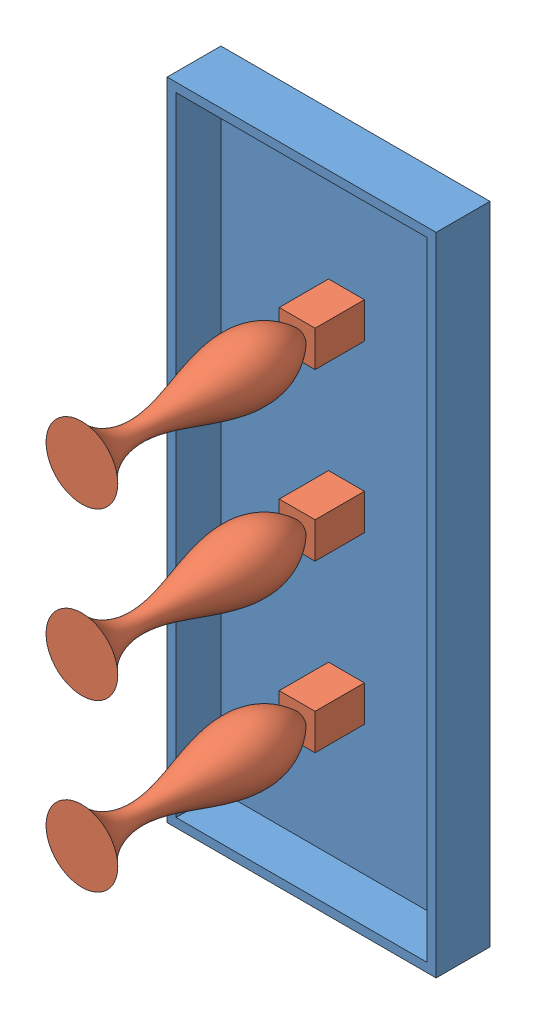
SolidWorks assembly Assem1, configuration Default. Lengths in mm.
Overall size (762 1828.8 774.7).
4 component instances, 2 part files, 9 mates.
Components (placement in the parent):
- Table_Top-1: Table_Top [Default] at (1737.8097 1152.1022 1538.3527) size (762 1828.8 152.4)
- Table_Leg-1: Table_Leg [Default] at (239.1087 1458.4963 2160.6527) x (1 0 0) z (0 1 0) size (237.21 762 237.21)
- Table_Leg-2: Table_Leg [Default] at (239.1087 988.5963 2160.6527) x (1 0 0) z (0 1 0) size (237.21 762 237.21)
- Table_Leg-3: Table_Leg [Default] at (239.1087 518.6963 2160.6527) x (1 0 0) z (0 1 0) size (237.21 762 237.21)
Mates (geometry in assembly coordinates):
- Coincident1: coincident anti-aligned: plane of Table_Top-1 through (1737.8097 1152.1022 1551.0527) normal (0 0 1); plane of Table_Leg-1 through (239.1087 1458.4963 1551.0527) normal (0 0 -1)
- Coincident2: coincident anti-aligned: plane of Table_Top-1 through (289.9087 1509.2963 1551.0527) normal (-1 0 0); plane of Table_Leg-1 through (289.9087 1407.6963 1551.0527) normal (1 0 0)
- Coincident3: coincident anti-aligned: plane of Table_Top-1 through (188.3087 1509.2963 1551.0527) normal (0 -1 0); plane of Table_Leg-1 through (188.3087 1509.2963 1551.0527) normal (0 1 0)
- Coincident4: coincident anti-aligned: plane of Table_Top-1 through (1737.8097 1152.1022 1551.0527) normal (0 0 1); plane of Table_Leg-2 through (239.1087 988.5963 1551.0527) normal (0 0 -1)
- Coincident5: coincident anti-aligned: plane of Table_Top-1 through (289.9087 1039.3963 1551.0527) normal (-1 0 0); plane of Table_Leg-2 through (289.9087 937.7963 1551.0527) normal (1 0 0)
- Coincident6: coincident anti-aligned: plane of Table_Top-1 through (188.3087 937.7963 1551.0527) normal (0 1 0); plane of Table_Leg-2 through (188.3087 937.7963 1551.0527) normal (0 -1 0)
- Coincident7: coincident anti-aligned: plane of Table_Top-1 through (1737.8097 1152.1022 1551.0527) normal (0 0 1); plane of Table_Leg-3 through (239.1087 518.6963 1551.0527) normal (0 0 -1)
- Coincident8: coincident anti-aligned: plane of Table_Top-1 through (289.9087 569.4963 1551.0527) normal (-1 0 0); plane of Table_Leg-3 through (289.9087 467.8963 1551.0527) normal (1 0 0)
- Coincident9: coincident anti-aligned: plane of Table_Top-1 through (188.3087 467.8963 1551.0527) normal (0 1 0); plane of Table_Leg-3 through (188.3087 467.8963 1551.0527) normal (0 -1 0)
